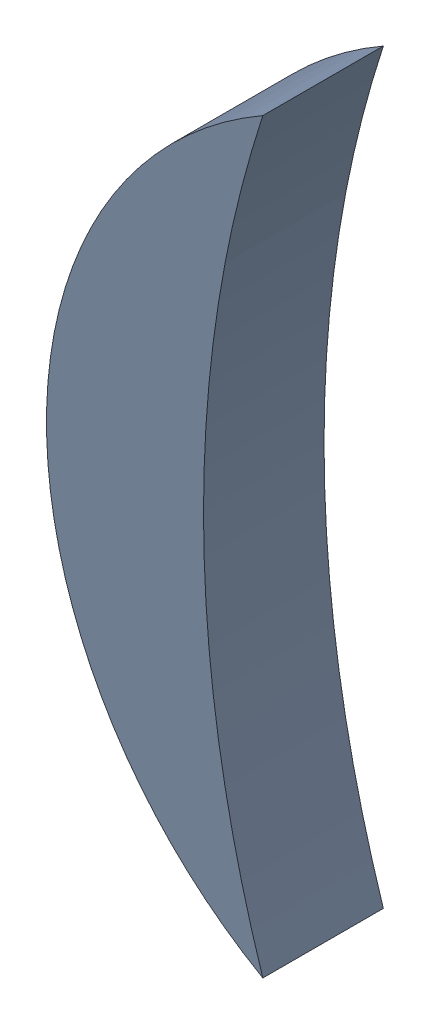
SolidWorks assembly Track (24.225mm,58.5mm)(24.5mm,58.5mm) on Top Layer, configuration Predeterminado. Lengths in mm.
Overall size (0.06 0.22 0.04).
2 component instances, 1 part files, 0 mates.
Components (placement in the parent):
- Track (24.225mm,58.5mm)(24.5mm,58.5mm) on Top Layer-1-1: Track (24.225mm,58.5mm)(24.5mm,58.5mm) on Top Layer-1 [Predeterminado] at (-68.317 -44.187 -0.0457) size (0.06 0.22 0.04)
  - Track (24.225mm,58.5mm)(24.5mm,58.5mm) on Top Layer-Part-1-1: Track (24.225mm,58.5mm)(24.5mm,58.5mm) on Top Layer-Part-1 [Predeterminado] at origin size (0.06 0.22 0.04)
